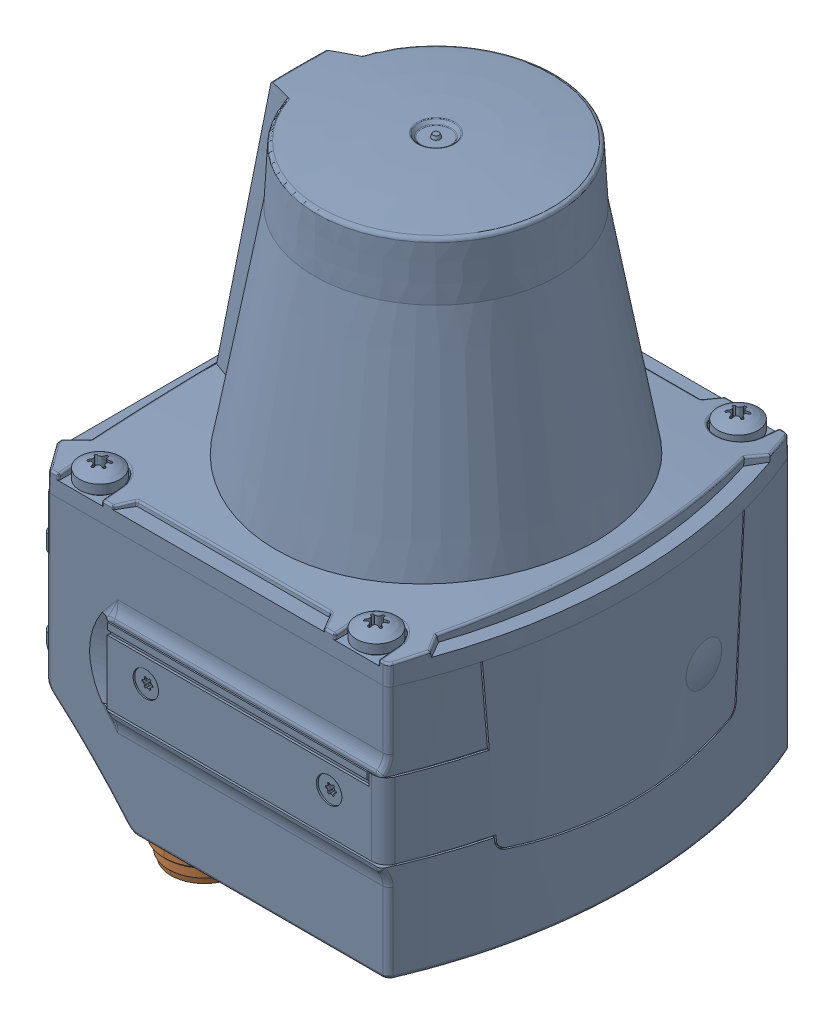
SolidWorks assembly Lidar_TIM561_V2, configuration Défaut. Lengths in mm.
Overall size (61.07 101.19 61.14).
2 component instances, 2 part files, 3 mates.
Components (placement in the parent):
- Lidar_TIM561_V2_1-1: Lidar_TIM561_V2_1 [Default] at (2.4655 -11.46 -0.2152) size (61 86.12 61.14)
- Lidar_TIM561_V2_2-1: Lidar_TIM561_V2_2 [Default] at (-6.0122 -3.1159 -0.216) x (0 1 -0.000098) z (0.000098 -0.000098 -1) size (31.3 16.2 37.7)
Mates (geometry in assembly coordinates):
- Coaxiale1: concentric: cylinder of Lidar_TIM561_V2_1-1 through (-19.8578 -25.3724 -0.2152) axis (0.707107 0.707107 0) radius 8.6; cylinder of Lidar_TIM561_V2_2-1 through (-16.1011 -21.6157 -0.2152) axis (0.707107 0.707107 0) radius 8.6
- Tangent1: tangent: sphere of Lidar_TIM561_V2_1-1; sphere of Lidar_TIM561_V2_2-1
- Parallèle4: parallel aligned: plane of Lidar_TIM561_V2_1-1 through (8.798 -12.2355 29.7848) normal (0 0 1); plane of Lidar_TIM561_V2_2-1 through (-22.0638 -25.9977 18.6348) normal (0 0 1)
